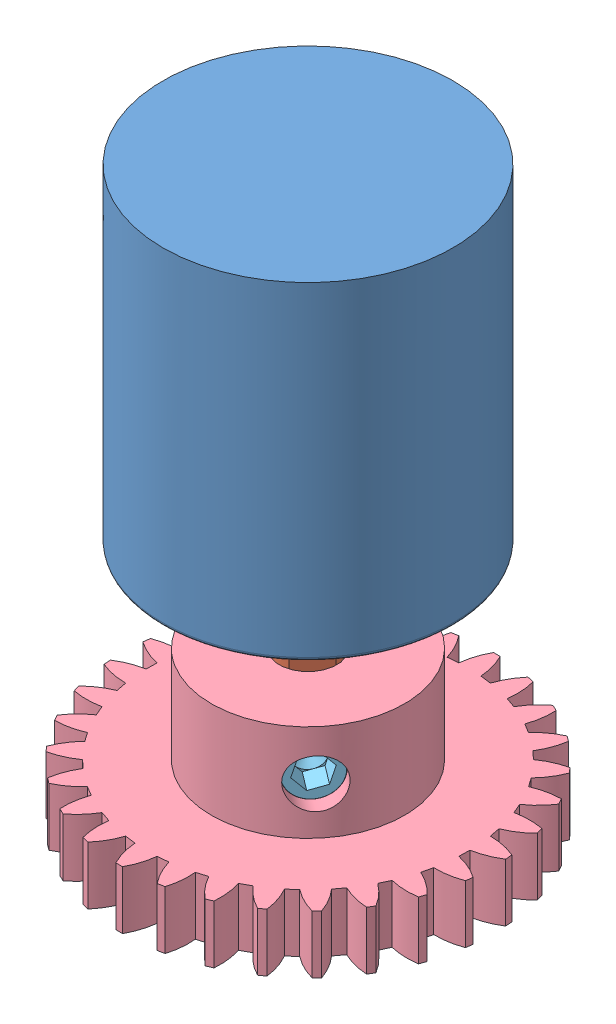
SolidWorks assembly Encoder, configuration 默认. Lengths in mm.
Overall size (26.83 29.68 26.85).
5 component instances, 5 part files, 8 mates.
Components (placement in the parent):
- Encoder_shell-1: Encoder_shell [默认] at (-8.4706 4.7172 17) size (15 17 15)
- Encoder_shaft-1: Encoder_shaft [默认] at (-8.4706 3.6176 17) x (-0.798174 0 -0.602427) z (-0.602427 0 0.798174) size (2.95 20.03 2.95)
- Encoder_bearing-1: Encoder_bearing [默认] at (-8.4706 -6.3824 17) x (0 1 0) z (-0.716589 0 0.697495) size (1.5 6.9 6.9)
- Encoder_gear-2: Encoder_gear [GB - Spur gear 0.6M 30T 20PA 3FW ---S30B10H8L3.0N] at (-8.4706 -16.062 17) x (0 -1 0) z (-0.602427 0 0.798174) size (8 19.13 19.2)
- encoder_gearScrew-1: encoder_gearScrew [GB_FASTENER_SCREWS_HSCP M3X3-N] at (-5.3536 -13.6193 19.8338) x (-0.798174 0 -0.602427) z (-0.172598 -0.958079 0.22868) size (3 3 3)
Mates (geometry in assembly coordinates):
- 同心1: concentric: cylinder of Encoder_shell-1 through (-8.4706 -15.1232 17) axis (0 -1 0) radius 3.5; cylinder of Encoder_bearing-1 through (-8.4706 -4.8824 17) axis (0 -1 0) radius 3.45
- 重合1: coincident: plane of Encoder_shell-1 through (-4.9706 -6.3824 17) normal (0 -1 0); plane of Encoder_bearing-1 through (-8.4706 -6.3824 17) normal (0 -1 0)
- 同心2: concentric: cylinder of Encoder_shaft-1 through (-8.4706 -16.3824 17) axis (0 1 0) radius 1.475; cylinder of Encoder_bearing-1 through (-8.4706 -4.8824 17) axis (0 -1 0) radius 1.48
- 重合4: coincident: plane of Encoder_shell-1 through (-4.9706 -6.3824 17) normal (0 -1 0); plane of Encoder_shaft-1 through (-8.4706 -6.3824 17) normal (0 1 0)
- 同心3: concentric: cylinder of Encoder_gear-2 through (-4.7111 -13.6193 20.3188) axis (0.798174 0 0.602427) radius 1.25; cylinder of encoder_gearScrew-1 through (6.4387 -13.6193 28.7341) axis (0.798174 0 0.602427) radius 1.5
- 重合5: coincident: plane of Encoder_shaft-1 through (-6.9959 -8.9624 17.0298) normal (0.798174 0 0.602427); plane of encoder_gearScrew-1 through (-7.7482 -13.6193 18.0265) normal (-0.798174 0 -0.602427)
- 同心4: concentric: cylinder of Encoder_shaft-1 through (-8.4706 -16.3824 17) axis (0 1 0) radius 1.475; cylinder of Encoder_gear-2 through (-8.4706 -24.0621 17) axis (0 1 0) radius 1.5
- 锁定1: lock: unknown of Encoder_shaft-1; unknown of encoder_gearScrew-1
